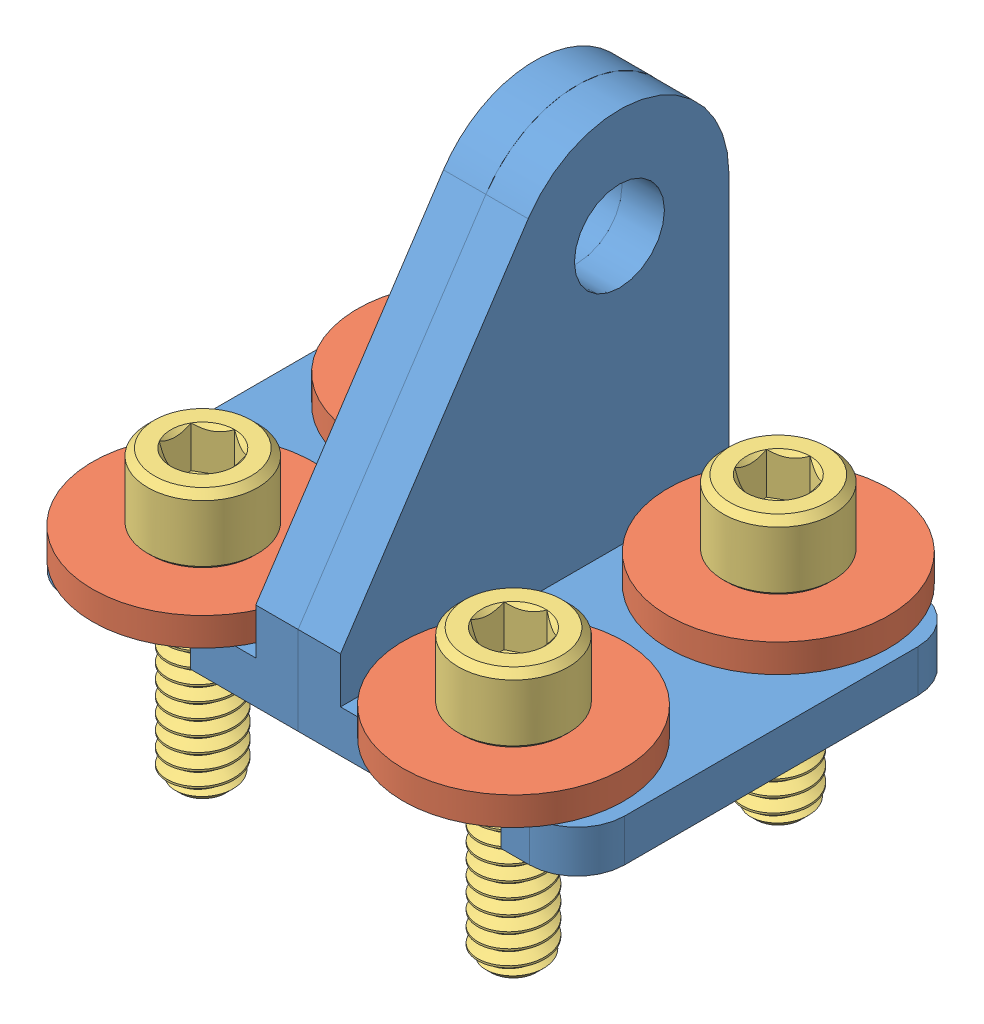
SolidWorks assembly Gimbal Side Bracket Assembly, configuration Default. Lengths in mm.
Overall size (40.13 41.41 34.93).
11 component instances, 3 part files, 16 mates.
Components (placement in the parent):
- Gimbal Side Bracket (NCM-PC075)-1: Gimbal Side Bracket (NCM-PC075) [NCM-PC075] at (-12.4825 -39.1491 22.9166) size (40.13 30.23 27.94)
  - NCM-PC075_NCMP-C-Bracket-1: NCM-PC075_NCMP-C-Bracket [075F] at origin size (20.07 30.23 27.94)
  - NCM-PC075_NCMP-C-Bracket-2: NCM-PC075_NCMP-C-Bracket [075R] x (-1 0 0) z (0 0 -1) size (20.07 30.23 27.94)
- SAE 025 Washer (MMC 91083A029)-1: SAE 025 Washer (MMC 91083A029) [91083A029] at (-23.6585 -34.0691 32.5686) x (0 -1 0) z (0 0 1) size (2.03 15.88 15.88)
- SAE 025 Washer (MMC 91083A029)-2: SAE 025 Washer (MMC 91083A029) [91083A029] at (-1.3065 -34.0691 32.5686) x (0 -1 0) z (0 0 1) size (2.03 15.88 15.88)
- SAE 025 Washer (MMC 91083A029)-3: SAE 025 Washer (MMC 91083A029) [91083A029] at (-23.6585 -34.0691 13.5186) x (0 -1 0) z (0 0 1) size (2.03 15.88 15.88)
- SAE 025 Washer (MMC 91083A029)-4: SAE 025 Washer (MMC 91083A029) [91083A029] at (-1.3065 -34.0691 13.5186) x (0 -1 0) z (0 0 1) size (2.03 15.88 15.88)
- Tab Bolt (MMC 91251A244)-1: Tab Bolt (MMC 91251A244) [91251A244] at (-1.3065 -49.9441 13.5186) x (1 0 0) z (0 -1 0) size (7.92 7.92 21.32)
- Tab Bolt (MMC 91251A244)-2: Tab Bolt (MMC 91251A244) [91251A244] at (-1.3065 -49.9441 32.5686) x (0.998673 0 0.051497) z (0 -1 0) size (7.92 7.92 21.32)
- Tab Bolt (MMC 91251A244)-3: Tab Bolt (MMC 91251A244) [91251A244] at (-23.6585 -49.9441 13.5186) x (1 0 0) z (0 -1 0) size (7.92 7.92 21.32)
- Tab Bolt (MMC 91251A244)-4: Tab Bolt (MMC 91251A244) [91251A244] at (-23.6585 -49.9441 32.5686) x (1 0 0) z (0 -1 0) size (7.92 7.92 21.32)
Mates (geometry in assembly coordinates):
- Concentric1: concentric anti-aligned: cylinder of Gimbal Side Bracket (NCM-PC075)-1/NCM-PC075_NCMP-C-Bracket-2 through (-23.6585 -36.1011 32.5686) axis (0 -1 0) radius 3.429; cylinder of SAE 025 Washer (MMC 91083A029)-1 through (-23.6585 -36.1011 32.5686) axis (0 1 0) radius 3.5687
- Coincident1: coincident anti-aligned: plane of Gimbal Side Bracket (NCM-PC075)-1/NCM-PC075_NCMP-C-Bracket-2 through (-23.6585 -36.1011 32.5686) normal (0 1 0); plane of SAE 025 Washer (MMC 91083A029)-1 through (-23.6585 -36.1011 32.5686) normal (0 -1 0)
- Concentric2: concentric anti-aligned: cylinder of Gimbal Side Bracket (NCM-PC075)-1/NCM-PC075_NCMP-C-Bracket-1 through (-1.3065 -36.1011 32.5686) axis (0 -1 0) radius 3.429; cylinder of SAE 025 Washer (MMC 91083A029)-2 through (-1.3065 -36.1011 32.5686) axis (0 1 0) radius 3.5687
- Coincident2: coincident anti-aligned: plane of Gimbal Side Bracket (NCM-PC075)-1/NCM-PC075_NCMP-C-Bracket-1 through (-1.3065 -36.1011 13.5186) normal (0 1 0); plane of SAE 025 Washer (MMC 91083A029)-2 through (-1.3065 -36.1011 32.5686) normal (0 -1 0)
- Concentric3: concentric anti-aligned: cylinder of Gimbal Side Bracket (NCM-PC075)-1/NCM-PC075_NCMP-C-Bracket-1 through (-1.3065 -36.1011 13.5186) axis (0 -1 0) radius 3.429; cylinder of SAE 025 Washer (MMC 91083A029)-4 through (-1.3065 -36.1011 13.5186) axis (0 1 0) radius 3.5687
- Coincident3: coincident anti-aligned: plane of Gimbal Side Bracket (NCM-PC075)-1/NCM-PC075_NCMP-C-Bracket-1 through (-1.3065 -36.1011 13.5186) normal (0 1 0); plane of SAE 025 Washer (MMC 91083A029)-4 through (-1.3065 -36.1011 13.5186) normal (0 -1 0)
- Concentric4: concentric anti-aligned: cylinder of Gimbal Side Bracket (NCM-PC075)-1/NCM-PC075_NCMP-C-Bracket-2 through (-23.6585 -36.1011 13.5186) axis (0 -1 0) radius 3.429; cylinder of SAE 025 Washer (MMC 91083A029)-3 through (-23.6585 -36.1011 13.5186) axis (0 1 0) radius 3.5687
- Coincident4: coincident anti-aligned: plane of Gimbal Side Bracket (NCM-PC075)-1/NCM-PC075_NCMP-C-Bracket-2 through (-23.6585 -36.1011 32.5686) normal (0 1 0); plane of SAE 025 Washer (MMC 91083A029)-3 through (-23.6585 -36.1011 13.5186) normal (0 -1 0)
- Concentric5: concentric anti-aligned: cylinder of SAE 025 Washer (MMC 91083A029)-4 through (-1.3065 -36.1011 13.5186) axis (0 1 0) radius 3.5687; cylinder of Tab Bolt (MMC 91251A244)-1 through (-1.3065 -29.2431 13.5186) axis (0 -1 0) radius 3.9624
- Coincident5: coincident anti-aligned: plane of SAE 025 Washer (MMC 91083A029)-4 through (-1.3065 -34.0691 13.5186) normal (0 1 0); plane of Tab Bolt (MMC 91251A244)-1 through (-1.3065 -34.0691 13.5186) normal (0 -1 0)
- Concentric6: concentric anti-aligned: cylinder of SAE 025 Washer (MMC 91083A029)-2 through (-1.3065 -36.1011 32.5686) axis (0 1 0) radius 3.5687; cylinder of Tab Bolt (MMC 91251A244)-2 through (-1.3065 -29.2431 32.5686) axis (0 -1 0) radius 3.9624
- Coincident6: coincident anti-aligned: plane of SAE 025 Washer (MMC 91083A029)-2 through (-1.3065 -34.0691 32.5686) normal (0 1 0); plane of Tab Bolt (MMC 91251A244)-2 through (-1.3065 -34.0691 32.5686) normal (0 -1 0)
- Concentric7: concentric anti-aligned: cylinder of SAE 025 Washer (MMC 91083A029)-3 through (-23.6585 -36.1011 13.5186) axis (0 1 0) radius 3.5687; cylinder of Tab Bolt (MMC 91251A244)-3 through (-23.6585 -29.2431 13.5186) axis (0 -1 0) radius 3.9624
- Coincident7: coincident anti-aligned: plane of SAE 025 Washer (MMC 91083A029)-3 through (-23.6585 -34.0691 13.5186) normal (0 1 0); plane of Tab Bolt (MMC 91251A244)-3 through (-23.6585 -34.0691 13.5186) normal (0 -1 0)
- Concentric8: concentric anti-aligned: cylinder of SAE 025 Washer (MMC 91083A029)-1 through (-23.6585 -36.1011 32.5686) axis (0 1 0) radius 3.5687; cylinder of Tab Bolt (MMC 91251A244)-4 through (-23.6585 -29.2431 32.5686) axis (0 -1 0) radius 3.9624
- Coincident8: coincident anti-aligned: plane of SAE 025 Washer (MMC 91083A029)-1 through (-23.6585 -34.0691 32.5686) normal (0 1 0); plane of Tab Bolt (MMC 91251A244)-4 through (-23.6585 -34.0691 32.5686) normal (0 -1 0)
